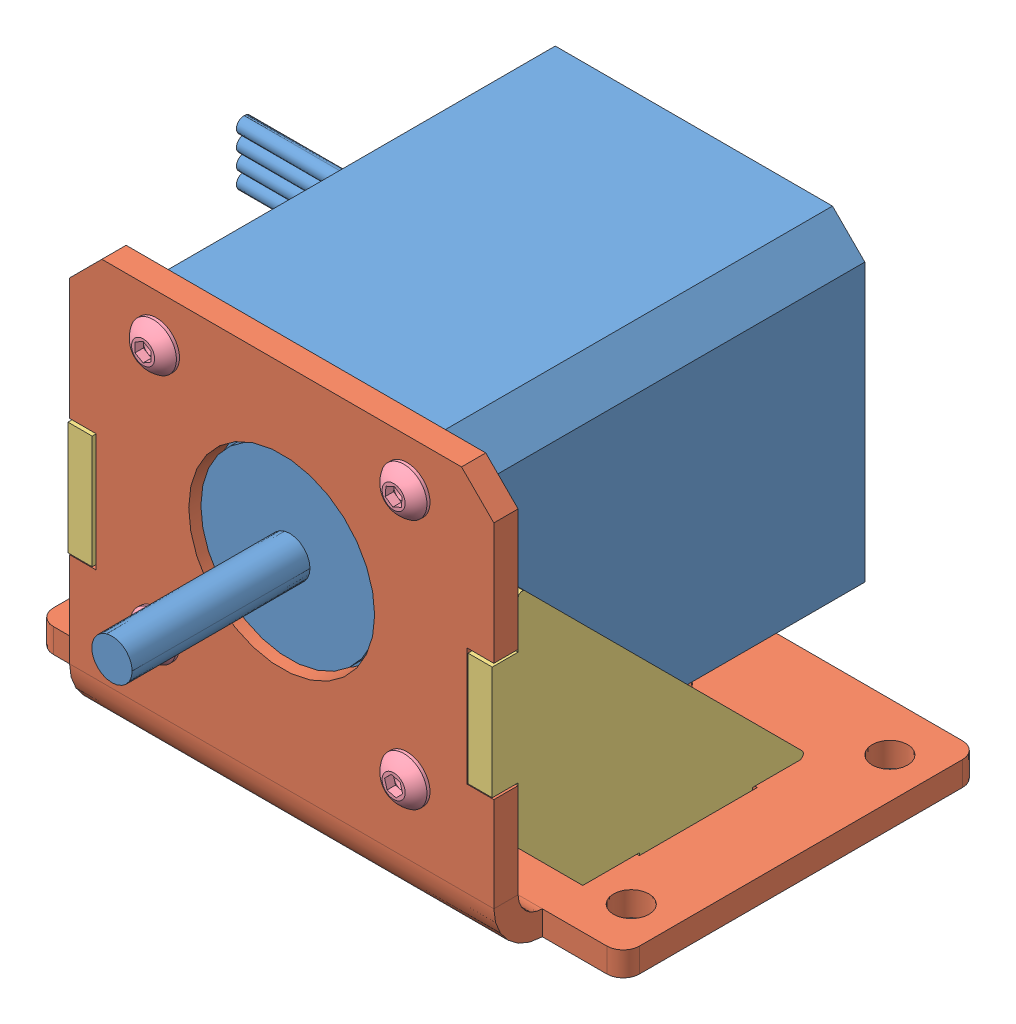
SolidWorks assembly NEMA_17_stand_assembled_01, configuration Default. Lengths in mm.
Overall size (82.4 51.55 72).
9 component instances, 4 part files, 11 mates.
Components (placement in the parent):
- NEMA_17-1: NEMA_17 [Default] at (21.15 8.95 0) x (-1 0 0) z (0 0 -1) size (67.3 42.3 72)
- NEMA_17_stand_welded-1: NEMA_17_stand_welded [Default] at origin size (72.5 51.55 50.2)
  - NEMA_17_stand_01-1: NEMA_17_stand_01 [Default] at (0 30.1 0) size (72.5 51.35 50)
  - Planka_01-1: Planka_01 [Default] at (-23.25 3 0) x (0 0 -1) z (1 0 0) size (38.49 38.49 3)
  - Planka_01-2: Planka_01 [Default] at (26.25 3 0) x (0 0 -1) z (1 0 0) size (38.49 38.49 3)
- B18.3.4M - 3 x 0.5 x 6 SBHCS --N-1: B18.3.4M - 3 x 0.5 x 6 SBHCS --N [B18.3.4M - 3 x 0.5 x 6 SBHCS --N] at (15.5 45.6 4.65) x (0 0 -1) z (0.996932 -0.078267 0) size (7.65 5.7 5.7)
- B18.3.4M - 3 x 0.5 x 6 SBHCS --N-2: B18.3.4M - 3 x 0.5 x 6 SBHCS --N [B18.3.4M - 3 x 0.5 x 6 SBHCS --N] at (-15.5 45.6 4.65) x (0 0 -1) z (1 0 0) size (7.65 5.7 5.7)
- B18.3.4M - 3 x 0.5 x 6 SBHCS --N-3: B18.3.4M - 3 x 0.5 x 6 SBHCS --N [B18.3.4M - 3 x 0.5 x 6 SBHCS --N] at (-15.5 14.6 4.65) x (0 0 -1) z (1 0 0) size (7.65 5.7 5.7)
- B18.3.4M - 3 x 0.5 x 6 SBHCS --N-4: B18.3.4M - 3 x 0.5 x 6 SBHCS --N [B18.3.4M - 3 x 0.5 x 6 SBHCS --N] at (15.5 14.6 4.65) x (0 0 -1) z (0.714128 -0.700015 0) size (7.65 5.7 5.7)
Mates (geometry in assembly coordinates):
- Concentric52: concentric: cylinder of assembly; cylinder of assembly; cylinder of NEMA_17-1 through (0 30.1 0) axis (0 0 -1) radius 11; cylinder of NEMA_17_stand_welded-1/NEMA_17_stand_01-1 through (0 30.1 3) axis (0 0 -1) radius 11.5
- Coincident100: coincident: plane of assembly; plane of assembly; plane of NEMA_17-1 through (21.15 8.95 0) normal (0 0 1); plane of NEMA_17_stand_welded-1/NEMA_17_stand_01-1 through (0 30.1 0) normal (0 0 -1)
- Parallel2: parallel: plane of assembly; plane of assembly; plane of NEMA_17-1 through (21.15 51.25 0) normal (0 1 0); plane of NEMA_17_stand_welded-1/NEMA_17_stand_01-1 through (26.25 51.35 3) normal (0 1 0)
- Concentric53: concentric: cylinder of assembly; cylinder of assembly; cylinder of NEMA_17_stand_welded-1/NEMA_17_stand_01-1 through (15.5 45.6 3) axis (0 0 1) radius 1.75; cylinder of B18.3.4M - 3 x 0.5 x 6 SBHCS --N-1 through (15.5 45.6 4.65) axis (0 0 1) radius 2.85
- Coincident101: coincident: plane of assembly; plane of assembly; plane of NEMA_17_stand_welded-1/NEMA_17_stand_01-1 through (0 30.1 3) normal (0 0 1); plane of B18.3.4M - 3 x 0.5 x 6 SBHCS --N-1 through (15.6174 47.0954 3) normal (0 0 -1)
- Concentric54: concentric: cylinder of assembly; cylinder of assembly; cylinder of NEMA_17_stand_welded-1/NEMA_17_stand_01-1 through (-15.5 45.6 3) axis (0 0 1) radius 1.75; cylinder of B18.3.4M - 3 x 0.5 x 6 SBHCS --N-2 through (-15.5 45.6 4.65) axis (0 0 1) radius 2.85
- Coincident102: coincident: plane of assembly; plane of assembly; plane of NEMA_17_stand_welded-1/NEMA_17_stand_01-1 through (0 30.1 3) normal (0 0 1); plane of B18.3.4M - 3 x 0.5 x 6 SBHCS --N-2 through (-15.5 47.1 3) normal (0 0 -1)
- Concentric55: concentric: cylinder of assembly; cylinder of assembly; cylinder of NEMA_17_stand_welded-1/NEMA_17_stand_01-1 through (-15.5 14.6 3) axis (0 0 1) radius 1.75; cylinder of B18.3.4M - 3 x 0.5 x 6 SBHCS --N-3 through (-15.5 14.6 4.65) axis (0 0 1) radius 2.85
- Coincident103: coincident: plane of assembly; plane of assembly; plane of NEMA_17_stand_welded-1/NEMA_17_stand_01-1 through (0 30.1 3) normal (0 0 1); plane of B18.3.4M - 3 x 0.5 x 6 SBHCS --N-3 through (-15.5 16.1 3) normal (0 0 -1)
- Concentric56: concentric: cylinder of assembly; cylinder of assembly; cylinder of NEMA_17_stand_welded-1/NEMA_17_stand_01-1 through (15.5 14.6 3) axis (0 0 1) radius 1.75; cylinder of B18.3.4M - 3 x 0.5 x 6 SBHCS --N-4 through (15.5 14.6 4.65) axis (0 0 1) radius 2.85
- Coincident104: coincident: plane of assembly; plane of assembly; plane of NEMA_17_stand_welded-1/NEMA_17_stand_01-1 through (0 30.1 3) normal (0 0 1); plane of B18.3.4M - 3 x 0.5 x 6 SBHCS --N-4 through (16.55 15.6712 3) normal (0 0 -1)
